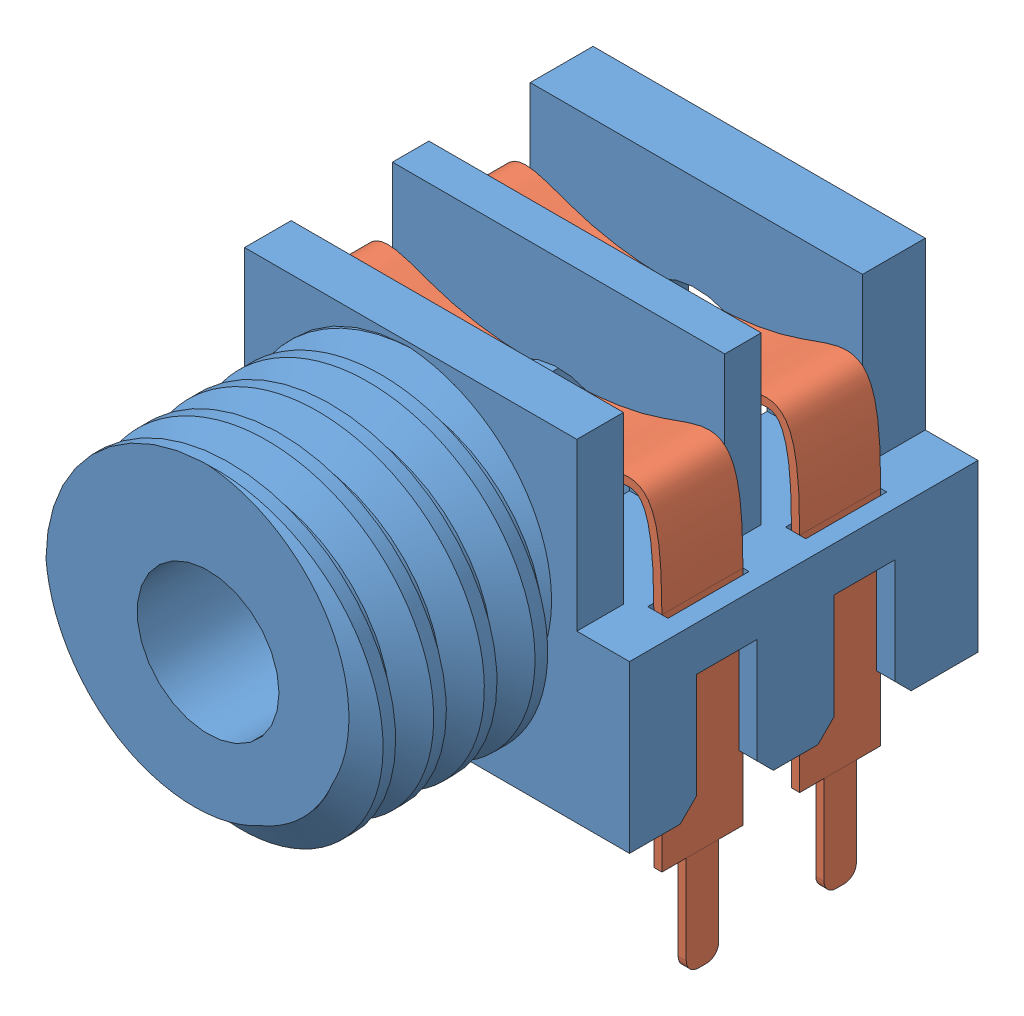
SolidWorks assembly Assem1, configuration Default. Lengths in mm.
Overall size (10.8 12.23 14.02).
3 component instances, 2 part files, 6 mates.
Components (placement in the parent):
- CL13843G_body-1: CL13843G_body [Default] at origin size (10.8 8.33 14.02)
- CL13843G_PINS-1: CL13843G_PINS [Default] at (-0.0001 -0.0046 -2.4) size (9.6 10.58 2)
- CL13843G_PINS-2: CL13843G_PINS [Default] at (-0.0001 -0.0046 -5.8) size (9.6 10.58 2)
Mates (geometry in assembly coordinates):
- Distance1: distance = 0.15 mm anti-aligned: plane of CL13843G_PINS-2 through (-4.8 -8 -4.8) normal (-1 0 0); plane of CL13843G_body-1 through (-4.95 4.5 -4.8) normal (1 0 0)
- Coincident2: coincident aligned: plane of CL13843G_PINS-1 through (-4.8 0.1857 -1.4) normal (-1 0 0); plane of CL13843G_PINS-2 through (-4.8 2.6857 -4.8) normal (-1 0 0)
- Coincident3: coincident anti-aligned: plane of CL13843G_body-1 through (-4.95 4.5 -6.8) normal (0 0 1); plane of CL13843G_PINS-2 through (-4.6002 2.6766 -6.8) normal (0 0 -1)
- Coincident4: coincident anti-aligned: plane of CL13843G_body-1 through (-4.95 4.5 -3.4) normal (0 0 1); plane of CL13843G_PINS-1 through (-4.6002 2.6766 -3.4) normal (0 0 -1)
- Coincident5: coincident aligned: plane of CL13843G_PINS-1 through (-4.8013 -5.5 -2.8) normal (0 -1 0); plane of CL13843G_PINS-2 through (-4.8013 -5.5 -6.2) normal (0 -1 0)
- Distance2: distance = 5.5 mm anti-aligned: plane of CL13843G_PINS-2 through (-4.8013 -5.5 -6.2) normal (0 -1 0); plane of CL13843G_body-1 through (4.1 0 -8.6) normal (0 1 0)
